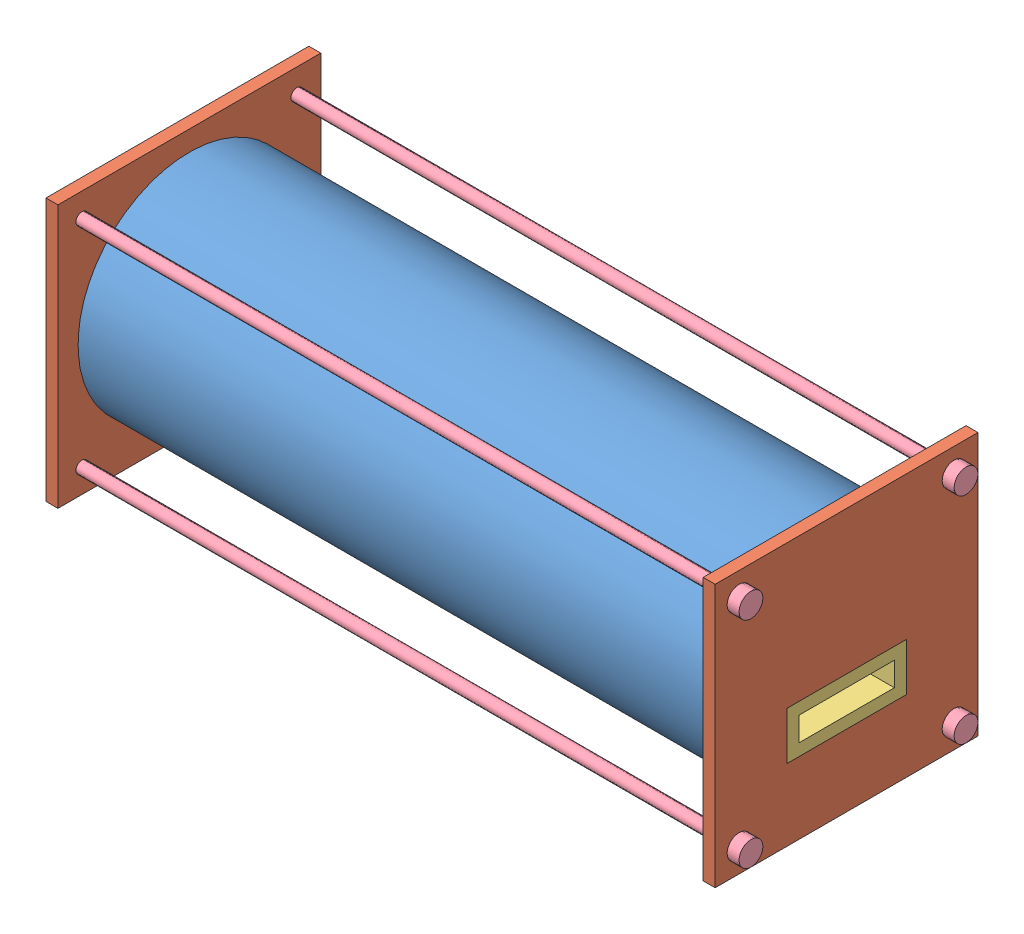
SolidWorks assembly Buoyancy Cylinder Assembly Properties Demo 1, configuration Default. Lengths in mm.
Overall size (580 220 220).
10 component instances, 5 part files, 3 mates.
Components (placement in the parent):
- Buoyancy Cylinder Assembly 1-2: Buoyancy Cylinder Assembly 1 [Default] at (29.2699 -73.6361 34.582) size (580 220 220)
  - Cylinder Body 1-1: Cylinder Body 1 [Default] at (-321.7289 98.8857 102.5905) size (550 186.35 186.35)
  - End Caps 1-1: End Caps 1 [Default] at (233.2711 -11.1143 -7.4095) x (-1 0 0) z (0 0 -1) size (10 220 220)
  - End Caps 1-2: End Caps 1 [Default] at (-326.7289 -11.1143 212.5905) size (10 220 220)
  - Water Channel 1-1: Water Channel 1 [Default] at (-326.7289 48.8857 152.5905) size (560 40 100)
  - End Cap Bolt 1-1: End Cap Bolt 1 [Default] at (-326.7289 8.8857 192.5905) size (580 20 20)
  - End Cap Bolt 1-2: End Cap Bolt 1 [Default] at (-326.7289 188.8857 192.5905) size (580 20 20)
  - End Cap Bolt 1-3: End Cap Bolt 1 [Default] at (-326.7289 8.8857 12.5905) size (580 20 20)
  - End Cap Bolt 1-4: End Cap Bolt 1 [Default] at (-326.7289 188.8857 12.5905) size (580 20 20)
- Cylinder Body Volume Demo 1-1: Cylinder Body Volume Demo 1 [Default] at (-287.459 25.2496 137.1724) size (540 166.35 166.35)
Mates (geometry in assembly coordinates):
- Coincident1: coincident anti-aligned: plane of Buoyancy Cylinder Assembly 1-2/End Caps 1-1 through (252.541 -84.7504 27.1724) normal (-1 0 0); plane of Cylinder Body Volume Demo 1-1 through (252.541 25.2496 137.1724) normal (1 0 0)
- Coincident2: coincident: plane of Buoyancy Cylinder Assembly 1-2/Water Channel 1-1 through (262.541 -24.7504 187.1724) normal (0 -1 0); plane of Cylinder Body Volume Demo 1-1 through (252.541 -24.7504 187.1724) normal (0 1 0)
- Coincident3: coincident aligned: circle of Buoyancy Cylinder Assembly 1-2/End Caps 1-2; cylinder of Cylinder Body Volume Demo 1-1 through (-287.459 25.2496 137.1724) axis (1 0 0) radius 83.1728
